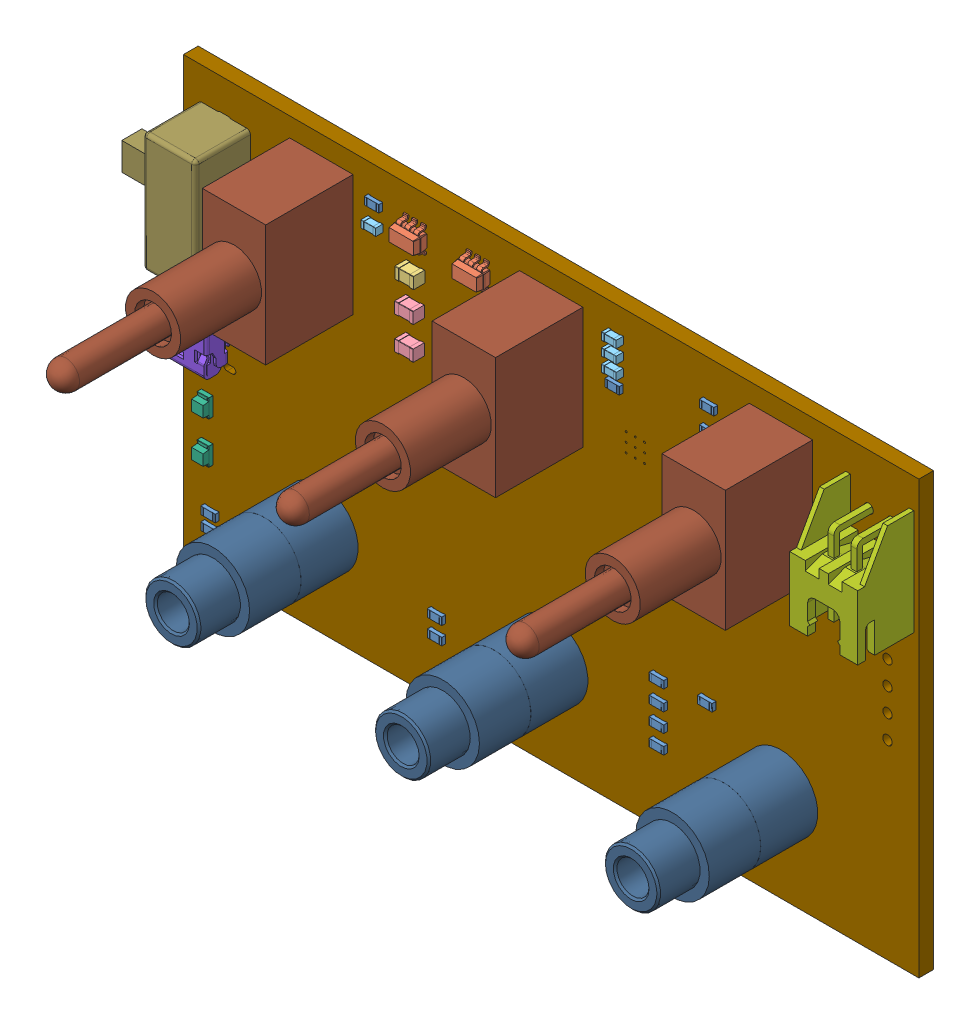
SolidWorks assembly PCB-assembly, configuration Default. Lengths in mm.
Overall size (82.41 47 32.65).
107 component instances, 22 part files, 21 mates.
Components (placement in the parent):
- ledTruck_PCB.step-1: ledTruck_PCB.step [Default] at (-218.1999 94.1524 35.3841) size (80.38 47 12.68)
  - ledTruck.step-1: ledTruck.step [Default] at origin size (80.38 47 12.68)
    - R_0603_1608Metric.step-1: R_0603_1608Metric.step [Default] at (162.2298 -104.8258 1.65) size (1.6 0.8 0.45)
      - SOLID.step-1: SOLID.step [Default] at origin size (1.6 0.8 0.45)
    - SOT-23-5.step-1: SOT-23-5.step [Default] at (130.302 -76.708 1.65) x (0 -1 0) z (0 0 1) size (2.8 2.9 1.55)
      - SOLID-0.step-1: SOLID-0.step [Default] at origin size (2.8 2.9 1.55)
    - SOT-23-5.step-2: SOT-23-5.step [Default] at (137.16 -76.708 1.65) x (0 -1 0) z (0 0 1) size (2.8 2.9 1.55)
      - SOLID-0.step-1: SOLID-0.step [Default] at origin size (2.8 2.9 1.55)
    - R_0603_1608Metric.step-2: R_0603_1608Metric.step [Default] at (162.433 -79.248 1.65) size (1.6 0.8 0.45)
      - SOLID.step-1: SOLID.step [Default] at origin size (1.6 0.8 0.45)
    - R_0603_1608Metric.step-3: R_0603_1608Metric.step [Default] at (162.433 -76.835 1.65) x (-1 0 0) z (0 0 1) size (1.6 0.8 0.45)
      - SOLID.step-1: SOLID.step [Default] at origin size (1.6 0.8 0.45)
    - R_0603_1608Metric.step-4: R_0603_1608Metric.step [Default] at (108.1929 -114.012 1.65) size (1.6 0.8 0.45)
      - SOLID.step-1: SOLID.step [Default] at origin size (1.6 0.8 0.45)
    - R_0603_1608Metric.step-5: R_0603_1608Metric.step [Default] at (108.1929 -115.512 1.65) size (1.6 0.8 0.45)
      - SOLID.step-1: SOLID.step [Default] at origin size (1.6 0.8 0.45)
    - R_0603_1608Metric.step-6: R_0603_1608Metric.step [Default] at (152.146 -80.01 1.65) size (1.6 0.8 0.45)
      - SOLID.step-1: SOLID.step [Default] at origin size (1.6 0.8 0.45)
    - R_0603_1608Metric.step-7: R_0603_1608Metric.step [Default] at (165.1 -84.836 1.65) x (0 1 0) z (0 0 1) size (1.6 0.8 0.45)
      - SOLID.step-1: SOLID.step [Default] at origin size (1.6 0.8 0.45)
    - R_0603_1608Metric.step-8: R_0603_1608Metric.step [Default] at (137.16 -80.264 1.65) x (-1 0 0) z (0 0 1) size (1.6 0.8 0.45)
      - SOLID.step-1: SOLID.step [Default] at origin size (1.6 0.8 0.45)
    - R_0603_1608Metric.step-9: R_0603_1608Metric.step [Default] at (156.972 -111.506 1.65) x (-1 0 0) z (0 0 1) size (1.6 0.8 0.45)
      - SOLID.step-1: SOLID.step [Default] at origin size (1.6 0.8 0.45)
    - R_0603_1608Metric.step-10: R_0603_1608Metric.step [Default] at (156.972 -107.442 1.65) size (1.6 0.8 0.45)
      - SOLID.step-1: SOLID.step [Default] at origin size (1.6 0.8 0.45)
    - R_0603_1608Metric.step-11: R_0603_1608Metric.step [Default] at (132.842 -113.284 1.65) size (1.6 0.8 0.45)
      - SOLID.step-1: SOLID.step [Default] at origin size (1.6 0.8 0.45)
    - R_0603_1608Metric.step-12: R_0603_1608Metric.step [Default] at (156.972 -109.474 1.65) x (-1 0 0) z (0 0 1) size (1.6 0.8 0.45)
      - SOLID.step-1: SOLID.step [Default] at origin size (1.6 0.8 0.45)
    - R_0603_1608Metric.step-13: R_0603_1608Metric.step [Default] at (156.972 -105.283 1.65) x (-1 0 0) z (0 0 1) size (1.6 0.8 0.45)
      - SOLID.step-1: SOLID.step [Default] at origin size (1.6 0.8 0.45)
    - R_0603_1608Metric.step-14: R_0603_1608Metric.step [Default] at (132.828 -111.379 1.65) size (1.6 0.8 0.45)
      - SOLID.step-1: SOLID.step [Default] at origin size (1.6 0.8 0.45)
    - L_0805_2012Metric.step-1: L_0805_2012Metric.step [Default] at (130.336 -80.264 1.65) x (-1 0 0) z (0 0 1) size (2 1.25 1.25)
      - SOLID-1.step-1: SOLID-1.step [Default] at origin size (2 1.25 1.25)
    - C_0805_2012Metric.step-1: C_0805_2012Metric.step [Default] at (130.302 -87.122 1.65) size (2 1.25 1.25)
      - SOLID-2.step-1: SOLID-2.step [Default] at origin size (2 1.25 1.25)
    - C_0603_1608Metric.step-1: C_0603_1608Metric.step [Default] at (152.146 -78.486 1.65) x (-1 0 0) z (0 0 1) size (1.6 0.8 0.8)
      - SOLID-3.step-1: SOLID-3.step [Default] at origin size (1.6 0.8 0.8)
    - C_0805_2012Metric.step-2: C_0805_2012Metric.step [Default] at (137.16 -83.566 1.65) size (2 1.25 1.25)
      - SOLID-2.step-1: SOLID-2.step [Default] at origin size (2 1.25 1.25)
    - C_0603_1608Metric.step-2: C_0603_1608Metric.step [Default] at (152.146 -76.962 1.65) x (-1 0 0) z (0 0 1) size (1.6 0.8 0.8)
      - SOLID-3.step-1: SOLID-3.step [Default] at origin size (1.6 0.8 0.8)
    - C_0603_1608Metric.step-3: C_0603_1608Metric.step [Default] at (152.146 -75.464 1.65) x (-1 0 0) z (0 0 1) size (1.6 0.8 0.8)
      - SOLID-3.step-1: SOLID-3.step [Default] at origin size (1.6 0.8 0.8)
    - C_0805_2012Metric.step-3: C_0805_2012Metric.step [Default] at (130.302 -83.566 1.65) size (2 1.25 1.25)
      - SOLID-2.step-1: SOLID-2.step [Default] at origin size (2 1.25 1.25)
    - C_0603_1608Metric.step-4: C_0603_1608Metric.step [Default] at (162.56 -81.534 1.65) size (1.6 0.8 0.8)
      - SOLID-3.step-1: SOLID-3.step [Default] at origin size (1.6 0.8 0.8)
    - C_0603_1608Metric.step-5: C_0603_1608Metric.step [Default] at (162.56 -88.138 1.65) size (1.6 0.8 0.8)
      - SOLID-3.step-1: SOLID-3.step [Default] at origin size (1.6 0.8 0.8)
    - C_0805_2012Metric.step-4: C_0805_2012Metric.step [Default] at (137.16 -87.122 1.65) size (2 1.25 1.25)
      - SOLID-2.step-1: SOLID-2.step [Default] at origin size (2 1.25 1.25)
    - R_0603_1608Metric.step-15: R_0603_1608Metric.step [Default] at (125.984 -75.946 1.65) size (1.6 0.8 0.45)
      - SOLID.step-1: SOLID.step [Default] at origin size (1.6 0.8 0.45)
    - R_0603_1608Metric.step-16: R_0603_1608Metric.step [Default] at (114.046 -80.264 1.65) x (0 -1 0) z (0 0 1) size (1.6 0.8 0.45)
      - SOLID.step-1: SOLID.step [Default] at origin size (1.6 0.8 0.45)
    - LED_0805_2012Metric.step-1: LED_0805_2012Metric.step [Default] at (107.6929 -108.512 1.65) x (0 -1 0) z (0 0 1) size (2 1.25 1.1)
      - SOLID-4.step-1: SOLID-4.step [Default] at origin size (2 1.25 1.1)
    - LED_0805_2012Metric.step-2: LED_0805_2012Metric.step [Default] at (107.6929 -103.962 1.65) x (0 -1 0) z (0 0 1) size (2 1.25 1.1)
      - SOLID-4.step-1: SOLID-4.step [Default] at origin size (2 1.25 1.1)
    - C_0603_1608Metric.step-6: C_0603_1608Metric.step [Default] at (125.984 -77.978 1.65) x (-1 0 0) z (0 0 1) size (1.6 0.8 0.8)
      - SOLID-3.step-1: SOLID-3.step [Default] at origin size (1.6 0.8 0.8)
    - SW_CuK_JS202011AQN_DPDT_Angled.step-1: SW_CuK_JS202011AQN_DPDT_Angled.step [Default] at (111.474 -79.012 1.65) x (0 -1 0) z (0 0 1) size (9 5.6 6.5) (hidden)
      - SOLID-5.step-1: SOLID-5.step [Default] at origin size (9 5.6 6.5)
    - JST_XH_S2B-XH-A_1x02_P2.50mm_Horizontal.step-1: JST_XH_S2B-XH-A_1x02_P2.50mm_Horizontal.step [Default] at (179.578 -78.012 1.65) size (7.4 11.5 9.5)
      - SOLID-6.step-1: SOLID-6.step [Default] at origin size (7.4 11.5 9.5)
    - USB_Micro-B_Molex_47346-0001.step-1: USB_Micro-B_Molex_47346-0001.step [Default] at (108.4213 -96.0044 1.65) x (0 -1 0) z (0 0 1) size (7.98 5.42 2.94)
      - SOLID-7.step-1: SOLID-7.step [Default] at origin size (7.98 5.42 2.94)
    - Crystal_SMD_0603-4Pin_6.0x3.5mm.step-1: Crystal_SMD_0603-4Pin_6.0x3.5mm.step [Default] at (162.56 -84.856 1.65) x (0 1 0) z (0 0 1) size (6 3.5 1.03)
      - SOLID-8.step-1: SOLID-8.step [Default] at origin size (6 3.5 1.03) (hidden)
    - 7101 ToggleSwitch.step-1: 7101 ToggleSwitch.step [Default] at (121.534 -82.012 10.15) size (0.36 0.5 1.28) (hidden)
      - SOLID-9.step-1: SOLID-9.step [Default] at origin size (0.28 0.5 0.35) (hidden)
      - SOLID-10.step-1: SOLID-10.step [Default] at origin size (0.24 0.24 0.35)
      - SOLID-11.step-1: SOLID-11.step [Default] at origin size (0.12 0.21 0.43)
      - SOLID-12.step-1: SOLID-12.step [Default] at origin size (0.36 0.31 0.06)
      - SOLID-13.step-1: SOLID-13.step [Default] at origin size (0.36 0.31 0.06)
      - SOLID-14.step-1: SOLID-14.step [Default] at origin size (0.08 0.03 0.16)
      - SOLID-15.step-1: SOLID-15.step [Default] at origin size (0.08 0.03 0.16)
      - SOLID-16.step-1: SOLID-16.step [Default] at origin size (0.08 0.03 0.16)
    - 7101 ToggleSwitch.step-2: 7101 ToggleSwitch.step [Default] at (146.534 -82.012 10.15) size (0.36 0.5 1.28) (hidden)
      - SOLID-9.step-1: SOLID-9.step [Default] at origin size (0.28 0.5 0.35) (hidden)
      - SOLID-10.step-1: SOLID-10.step [Default] at origin size (0.24 0.24 0.35)
      - SOLID-11.step-1: SOLID-11.step [Default] at origin size (0.12 0.21 0.43)
      - SOLID-12.step-1: SOLID-12.step [Default] at origin size (0.36 0.31 0.06)
      - SOLID-13.step-1: SOLID-13.step [Default] at origin size (0.36 0.31 0.06)
      - SOLID-14.step-1: SOLID-14.step [Default] at origin size (0.08 0.03 0.16)
      - SOLID-15.step-1: SOLID-15.step [Default] at origin size (0.08 0.03 0.16)
      - SOLID-16.step-1: SOLID-16.step [Default] at origin size (0.08 0.03 0.16)
    - 7101 ToggleSwitch.step-3: 7101 ToggleSwitch.step [Default] at (171.534 -82.012 10.15) size (0.36 0.5 1.28) (hidden)
      - SOLID-9.step-1: SOLID-9.step [Default] at origin size (0.28 0.5 0.35) (hidden)
      - SOLID-10.step-1: SOLID-10.step [Default] at origin size (0.24 0.24 0.35)
      - SOLID-11.step-1: SOLID-11.step [Default] at origin size (0.12 0.21 0.43)
      - SOLID-12.step-1: SOLID-12.step [Default] at origin size (0.36 0.31 0.06)
      - SOLID-13.step-1: SOLID-13.step [Default] at origin size (0.36 0.31 0.06)
      - SOLID-14.step-1: SOLID-14.step [Default] at origin size (0.08 0.03 0.16)
      - SOLID-15.step-1: SOLID-15.step [Default] at origin size (0.08 0.03 0.16)
      - SOLID-16.step-1: SOLID-16.step [Default] at origin size (0.08 0.03 0.16)
    - COMPOUND.step-1: COMPOUND.step [Default] at origin size (80 47 1.6)
- 3,5mmjack-1: 3,5mmjack [Default] at (-98.1659 -15.3596 36.9841) size (8 8 18.3)
- 3,5mmjack-2: 3,5mmjack [Default] at (-73.1659 -15.3596 36.9841) size (8 8 18.3)
- 3,5mmjack-3: 3,5mmjack [Default] at (-48.1659 -15.3596 36.9841) size (8 8 18.3)
- toggle-switch-2: toggle-switch [Default] at (-47.8013 13.9041 36.9841) x (1 0 0) z (0 -1 0) size (6.9 31.5 13.2)
- toggle-switch-3: toggle-switch [Default] at (-72.8013 13.9041 36.9841) x (1 0 0) z (0 -1 0) size (6.9 31.5 13.2)
- toggle-switch-4: toggle-switch [Default] at (-97.8013 13.9041 36.9841) x (1 0 0) z (0 -1 0) size (6.9 31.5 13.2)
- slideswitch-1: slideswitch [Default] at (-109.6165 12.0841 36.9841) x (0 -1 0) z (-1 0 0) size (13 8.2 9.7)
Mates (geometry in assembly coordinates):
- Coincident1: coincident anti-aligned: plane of ledTruck_PCB.step-1/ledTruck.step-1/COMPOUND.step-1 through (-73.1659 -1.8596 36.9841) normal (0 0 1); plane of 3,5mmjack-1 through (-98.1659 -15.3596 36.9841) normal (0 0 -1)
- Coincident2: coincident anti-aligned: plane of ledTruck_PCB.step-1/ledTruck.step-1/COMPOUND.step-1 through (-100.2659 -16.2596 35.3841) normal (-1 0 0); plane of 3,5mmjack-1 through (-100.2659 -14.4596 34.9841) normal (1 0 0)
- Coincident3: coincident anti-aligned: plane of ledTruck_PCB.step-1/ledTruck.step-1/COMPOUND.step-1 through (-99.0659 -13.2596 35.3841) normal (0 1 0); plane of 3,5mmjack-1 through (-97.2659 -13.2596 34.9841) normal (0 -1 0)
- Coincident4: coincident anti-aligned: plane of ledTruck_PCB.step-1/ledTruck.step-1/COMPOUND.step-1 through (-73.1659 -1.8596 36.9841) normal (0 0 1); plane of 3,5mmjack-2 through (-73.1659 -15.3596 36.9841) normal (0 0 -1)
- Coincident5: coincident anti-aligned: plane of ledTruck_PCB.step-1/ledTruck.step-1/COMPOUND.step-1 through (-75.2659 -16.2596 35.3841) normal (-1 0 0); plane of 3,5mmjack-2 through (-75.2659 -14.4596 34.9841) normal (1 0 0)
- Coincident6: coincident anti-aligned: plane of ledTruck_PCB.step-1/ledTruck.step-1/COMPOUND.step-1 through (-73.1659 -1.8596 36.9841) normal (0 0 1); plane of 3,5mmjack-3 through (-48.1659 -15.3596 36.9841) normal (0 0 -1)
- Coincident7: coincident anti-aligned: plane of ledTruck_PCB.step-1/ledTruck.step-1/COMPOUND.step-1 through (-50.2659 -16.2596 35.3841) normal (-1 0 0); plane of 3,5mmjack-3 through (-50.2659 -14.4596 34.9841) normal (1 0 0)
- Coincident8: coincident anti-aligned: plane of ledTruck_PCB.step-1/ledTruck.step-1/COMPOUND.step-1 through (-49.0659 -13.2596 35.3841) normal (0 1 0); plane of 3,5mmjack-3 through (-47.2659 -13.2596 34.9841) normal (0 -1 0)
- Coincident12: coincident anti-aligned: plane of ledTruck_PCB.step-1/ledTruck.step-1/COMPOUND.step-1 through (-74.0659 -13.2596 35.3841) normal (0 1 0); plane of 3,5mmjack-2 through (-72.2659 -13.2596 34.9841) normal (0 -1 0)
- Coincident13: coincident anti-aligned: plane of ledTruck_PCB.step-1/ledTruck.step-1/COMPOUND.step-1 through (-73.1659 -1.8596 36.9841) normal (0 0 1); plane of toggle-switch-2 through (-47.8013 13.9041 36.9841) normal (0 0 -1)
- Coincident14: coincident anti-aligned: plane of ledTruck_PCB.step-1/ledTruck.step-1/COMPOUND.step-1 through (-47.5659 8.7904 35.3841) normal (0 -1 0); plane of toggle-switch-2 through (-48.7659 8.7904 34.7841) normal (0 1 0)
- Concentric5: concentric anti-aligned: cylinder of ledTruck_PCB.step-1/ledTruck.step-1/COMPOUND.step-1 through (-47.5659 8.1404 35.3841) axis (0 0 -1) radius 0.65; cylinder of toggle-switch-2 through (-47.5659 8.1404 34.7841) axis (0 0 1) radius 0.65
- Coincident17: coincident anti-aligned: plane of ledTruck_PCB.step-1/ledTruck.step-1/COMPOUND.step-1 through (-73.1659 -1.8596 36.9841) normal (0 0 1); plane of toggle-switch-3 through (-72.8013 13.9041 36.9841) normal (0 0 -1)
- Coincident18: coincident anti-aligned: plane of ledTruck_PCB.step-1/ledTruck.step-1/COMPOUND.step-1 through (-72.5659 8.7904 35.3841) normal (0 -1 0); plane of toggle-switch-3 through (-73.7659 8.7904 34.7841) normal (0 1 0)
- Concentric6: concentric anti-aligned: cylinder of ledTruck_PCB.step-1/ledTruck.step-1/COMPOUND.step-1 through (-72.5659 8.1404 35.3841) axis (0 0 -1) radius 0.65; cylinder of toggle-switch-3 through (-72.5659 8.1404 34.7841) axis (0 0 1) radius 0.65
- Coincident19: coincident anti-aligned: plane of ledTruck_PCB.step-1/ledTruck.step-1/COMPOUND.step-1 through (-73.1659 -1.8596 36.9841) normal (0 0 1); plane of toggle-switch-4 through (-97.8013 13.9041 36.9841) normal (0 0 -1)
- Coincident20: coincident anti-aligned: plane of ledTruck_PCB.step-1/ledTruck.step-1/COMPOUND.step-1 through (-97.5659 8.7904 35.3841) normal (0 -1 0); plane of toggle-switch-4 through (-98.7659 8.7904 34.7841) normal (0 1 0)
- Concentric7: concentric anti-aligned: cylinder of ledTruck_PCB.step-1/ledTruck.step-1/COMPOUND.step-1 through (-97.5659 8.1404 35.3841) axis (0 0 -1) radius 0.65; cylinder of toggle-switch-4 through (-97.5659 8.1404 34.7841) axis (0 0 1) radius 0.65
- Coincident22: coincident: plane of ledTruck_PCB.step-1/ledTruck.step-1/COMPOUND.step-1 through (-73.1659 -1.8596 36.9841) normal (0 0 1); plane of slideswitch-1 through (-109.6165 12.0841 36.9841) normal (0 0 -1)
- Concentric8: concentric: cylinder of ledTruck_PCB.step-1/ledTruck.step-1/COMPOUND.step-1 through (-108.7259 14.6404 34.5841) axis (0 0 1) radius 0.5; cylinder of slideswitch-1 through (-108.7259 14.6404 34.7841) axis (0 0 1) radius 0.4
- Concentric9: concentric aligned: cylinder of ledTruck_PCB.step-1/ledTruck.step-1/COMPOUND.step-1 through (-108.7259 11.6404 34.5841) axis (0 0 1) radius 0.5; cylinder of slideswitch-1 through (-108.7259 11.6404 34.7841) axis (0 0 1) radius 0.4
